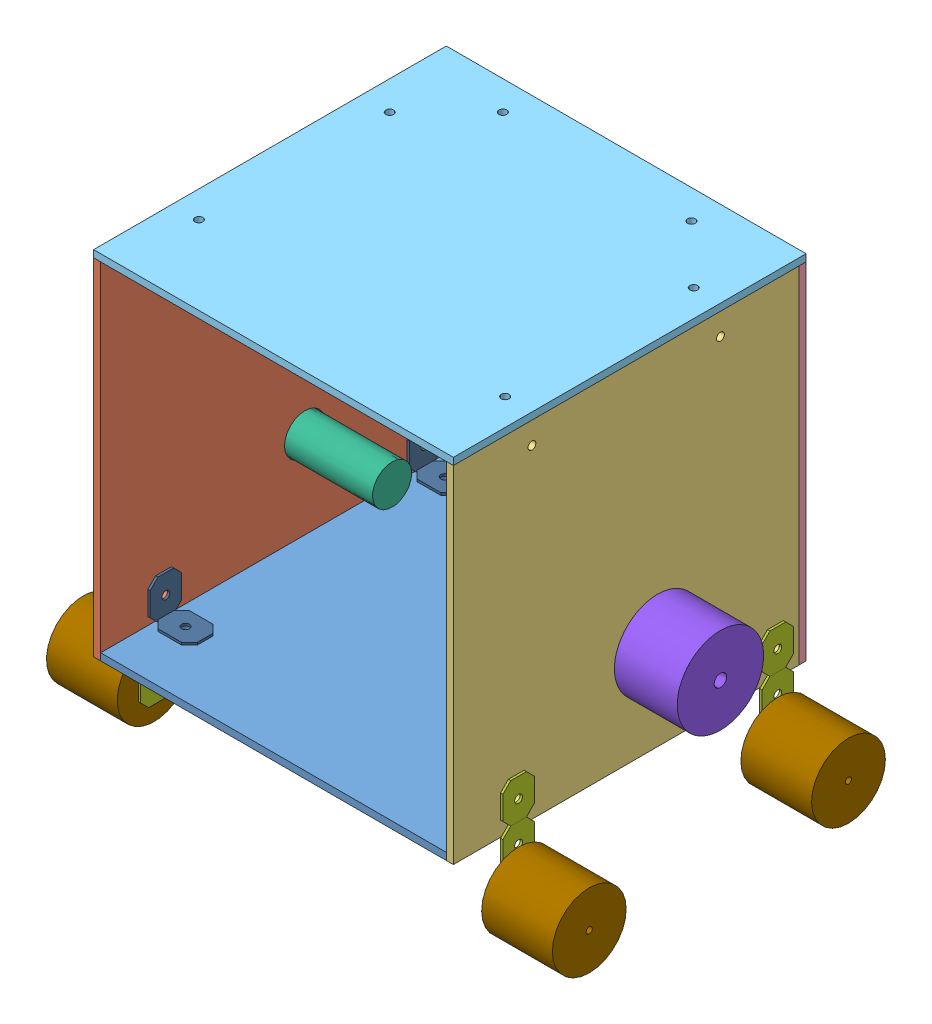
SolidWorks assembly walle, configuration Default. Lengths in mm.
Overall size (322 289.64 228.5).
29 component instances, 10 part files, 77 mates.
Components (placement in the parent):
- bottom-1: bottom [Default] at (91.1986 106.7408 168.0304) size (220 4.5 220)
- left-1: left [Default] at (-18.8014 216.7408 168.0304) x (0 0 1) z (0 -1 0) size (220 4.5 220)
- right-1: right [Default] at (201.1986 216.7408 168.0304) x (0 0 -1) z (0 -1 0) size (220 4.5 220)
- back-1: back [Default] at (91.1986 216.7408 58.0304) x (1 0 0) z (0 1 0) size (229 4.5 220)
- top-1: top [Default] at (91.1986 326.7408 165.7804) size (229 4.5 224.5)
- motor-1: motor [Default] at (36.6986 166.7408 148.0304) x (0 -0.263178 0.964747) z (0 -0.964747 -0.263178) size (25 70 25)
- motor-2: motor [Default] at (145.6986 163.3094 148.0304) x (0 0.57906 -0.815285) z (0 -0.815285 -0.57906) size (25 70 25)
- legs-1: legs [Default] at (-11.4617 88.7118 53.8984) x (0 1 0) z (0 0 1) size (75 1.5 20)
- legs-2: legs [Default] at (-36.6412 108.7699 218.8984) x (0 -1 0) z (0 0 1) size (75 1.5 20)
- legs-3: legs [Default] at (193.8588 108.7699 218.8984) x (0 -1 0) z (0 0 1) size (75 1.5 20)
- legs-4: legs [Default] at (193.8588 108.7699 53.8984) x (0 -1 0) z (0 0 1) size (75 1.5 20)
- big wheel-1: big wheel [Default] at (-23.3014 166.7408 148.0304) x (0 0.828484 0.560012) z (0 -0.560012 0.828484) size (55 40 55)
- big wheel-2: big wheel [Default] at (245.6986 163.3094 148.0304) x (0 -0.121677 0.99257) z (0 -0.99257 -0.121677) size (55 40 55)
- side wheels-1: side wheels [Default] at (-69.8014 73.7408 73.0304) x (0 -1 0) z (0 0 1) size (47 45 47)
- side wheels-2: side wheels [Default] at (-24.8014 73.7408 238.0304) x (0 0.863971 -0.503542) z (0 0.503542 0.863971) size (47 45 47)
- side wheels-3: side wheels [Default] at (252.1986 73.7408 238.0304) x (0 1 0) z (0 0 1) size (47 45 47)
- side wheels-4: side wheels [Default] at (252.1986 73.7408 73.0304) x (0 1 0) z (0 0 1) size (47 45 47)
- 2arm-1: 2arm [Default] at (10.1695 99.4011 218.8984) size (26.5 25 20)
- 2arm-2: 2arm [Default] at (10.1695 99.4011 53.8984) size (26.5 25 20)
- 2arm-3: 2arm [Default] at (50.3305 99.4011 87.0013) x (0 0 1) z (-1 0 0) size (26.5 25 20)
- 2arm-4: 2arm [Default] at (170.3305 99.4011 87.0013) x (0 0 1) z (-1 0 0) size (26.5 25 20)
- 2arm-5: 2arm [Default] at (172.2276 99.4011 92.1623) x (-1 0 0) z (0 0 -1) size (26.5 25 20)
- 2arm-6: 2arm [Default] at (172.2276 99.4011 257.1623) x (-1 0 0) z (0 0 -1) size (26.5 25 20)
- 2arm-7: 2arm [Default] at (12.0666 338.5806 87.0013) x (0 0 1) z (1 0 0) size (26.5 25 20)
- 2arm-8: 2arm [Default] at (132.0666 338.5806 87.0013) x (0 0 1) z (1 0 0) size (26.5 25 20)
- 2arm-9: 2arm [Default] at (-30.6412 297.7699 208.8984) x (0 -1 0) z (0 0 1) size (26.5 25 20)
- 2arm-10: 2arm [Default] at (213.0383 297.7699 247.1623) x (0 -1 0) z (0 0 -1) size (26.5 25 20)
- 2arm-11: 2arm [Default] at (213.0383 297.7699 127.1623) x (0 -1 0) z (0 0 -1) size (26.5 25 20)
- 2arm-12: 2arm [Default] at (10.1695 338.5806 127.1623) x (1 0 0) z (0 0 -1) size (26.5 25 20)
Mates (geometry in assembly coordinates):
- Coincident1: coincident anti-aligned: plane of bottom-1 through (201.1986 111.2408 278.0304) normal (1 0 0); plane of right-1 through (201.1986 216.7408 168.0304) normal (-1 0 0)
- Coincident2: coincident aligned: plane of bottom-1 through (91.1986 106.7408 168.0304) normal (0 -1 0); plane of right-1 through (205.6986 106.7408 278.0304) normal (0 -1 0)
- Coincident3: coincident aligned: plane of bottom-1 through (-18.8014 111.2408 278.0304) normal (0 0 1); plane of right-1 through (205.6986 106.7408 278.0304) normal (0 0 1)
- Coincident4: coincident aligned: plane of bottom-1 through (91.1986 106.7408 168.0304) normal (0 -1 0); plane of left-1 through (-23.3014 106.7408 58.0304) normal (0 -1 0)
- Coincident5: coincident anti-aligned: plane of bottom-1 through (-18.8014 111.2408 278.0304) normal (-1 0 0); plane of left-1 through (-18.8014 216.7408 168.0304) normal (1 0 0)
- Coincident6: coincident aligned: plane of bottom-1 through (-18.8014 111.2408 278.0304) normal (0 0 1); plane of left-1 through (-23.3014 106.7408 278.0304) normal (0 0 1)
- Coincident10: coincident aligned: plane of right-1 through (205.6986 216.7408 168.0304) normal (1 0 0); plane of back-1 through (205.6986 326.7408 53.5304) normal (1 0 0)
- Coincident11: coincident aligned: plane of bottom-1 through (91.1986 106.7408 168.0304) normal (0 -1 0); plane of back-1 through (-23.3014 106.7408 53.5304) normal (0 -1 0)
- Coincident12: coincident anti-aligned: plane of right-1 through (205.6986 106.7408 58.0304) normal (0 0 -1); plane of back-1 through (91.1986 216.7408 58.0304) normal (0 0 1)
- Coincident13: coincident aligned: plane of left-1 through (-23.3014 106.7408 278.0304) normal (0 0 1); plane of top-1 through (-23.3014 331.2408 278.0304) normal (0 0 1)
- Coincident14: coincident anti-aligned: plane of left-1 through (-23.3014 326.7408 58.0304) normal (0 1 0); plane of top-1 through (91.1986 326.7408 165.7804) normal (0 -1 0)
- Coincident15: coincident aligned: plane of left-1 through (-23.3014 216.7408 168.0304) normal (-1 0 0); plane of top-1 through (-23.3014 331.2408 278.0304) normal (-1 0 0)
- Concentric1: concentric anti-aligned: cylinder of right-1 through (201.1976 163.3094 148.0304) axis (1 0 0) radius 13; cylinder of motor-2 through (215.6986 163.3094 148.0304) axis (-1 0 0) radius 2
- Concentric2: concentric anti-aligned: cylinder of left-1 through (-18.8004 166.7408 148.0304) axis (-1 0 0) radius 13; cylinder of motor-1 through (-33.3014 166.7408 148.0304) axis (1 0 0) radius 2
- Coincident26: coincident anti-aligned: plane of left-1 through (-23.3014 216.7408 168.0304) normal (-1 0 0); plane of legs-2 through (-23.3014 123.7408 238.0304) normal (1 0 0)
- Coincident28: coincident anti-aligned: plane of left-1 through (-23.3014 216.7408 168.0304) normal (-1 0 0); plane of legs-1 through (-23.3014 123.7408 73.0304) normal (1 0 0)
- Coincident30: coincident anti-aligned: plane of right-1 through (205.6986 216.7408 168.0304) normal (1 0 0); plane of legs-3 through (205.6986 123.7408 238.0304) normal (-1 0 0)
- Coincident31: coincident anti-aligned: plane of right-1 through (205.6986 216.7408 168.0304) normal (1 0 0); plane of legs-4 through (205.6986 123.7408 73.0304) normal (-1 0 0)
- Coincident32: coincident aligned: plane of left-1 through (-23.3014 216.7408 168.0304) normal (-1 0 0); plane of motor-1 through (-23.3014 166.7408 148.0304) normal (-1 0 0)
- Coincident33: coincident aligned: plane of right-1 through (205.6986 216.7408 168.0304) normal (1 0 0); plane of motor-2 through (205.6986 163.3094 148.0304) normal (1 0 0)
- Concentric3: concentric anti-aligned: cylinder of motor-1 through (-33.3014 166.7408 148.0304) axis (1 0 0) radius 2; cylinder of big wheel-1 through (-23.3014 166.7408 148.0304) axis (-1 0 0) radius 4
- Coincident34: coincident anti-aligned: plane of left-1 through (-23.3014 216.7408 168.0304) normal (-1 0 0); plane of big wheel-1 through (-23.3014 166.7408 148.0304) normal (1 0 0)
- Concentric4: concentric aligned: cylinder of motor-2 through (215.6986 163.3094 148.0304) axis (-1 0 0) radius 2; cylinder of big wheel-2 through (245.6986 163.3094 148.0304) axis (-1 0 0) radius 4
- Coincident35: coincident anti-aligned: plane of right-1 through (205.6986 216.7408 168.0304) normal (1 0 0); plane of big wheel-2 through (205.6986 163.3094 148.0304) normal (-1 0 0)
- Concentric5: concentric anti-aligned: cylinder of legs-2 through (-24.8014 73.7408 238.0304) axis (1 0 0) radius 2.5; cylinder of side wheels-2 through (-24.8004 73.7408 238.0304) axis (-1 0 0) radius 2
- Coincident36: coincident anti-aligned: plane of legs-2 through (-24.8014 73.7408 238.0304) normal (-1 0 0); plane of side wheels-2 through (-24.8014 73.7408 238.0304) normal (1 0 0)
- Coincident37: coincident anti-aligned: plane of legs-1 through (-24.8014 73.7408 73.0304) normal (-1 0 0); plane of side wheels-1 through (-24.8014 73.7408 73.0304) normal (1 0 0)
- Concentric6: concentric anti-aligned: cylinder of legs-1 through (-23.3014 73.7408 73.0304) axis (-1 0 0) radius 2.5; cylinder of side wheels-1 through (-69.8024 73.7408 73.0304) axis (1 0 0) radius 2
- Coincident38: coincident anti-aligned: plane of legs-4 through (207.1986 73.7408 73.0304) normal (1 0 0); plane of side wheels-4 through (207.1986 73.7408 73.0304) normal (-1 0 0)
- Concentric7: concentric anti-aligned: cylinder of legs-4 through (205.6986 73.7408 73.0304) axis (1 0 0) radius 2.5; cylinder of side wheels-4 through (252.1996 73.7408 73.0304) axis (-1 0 0) radius 2
- Coincident39: coincident anti-aligned: plane of legs-3 through (207.1986 73.7408 238.0304) normal (1 0 0); plane of side wheels-3 through (207.1986 73.7408 238.0304) normal (-1 0 0)
- Concentric8: concentric anti-aligned: cylinder of legs-3 through (205.6986 73.7408 238.0304) axis (1 0 0) radius 2.5; cylinder of side wheels-3 through (252.1996 73.7408 238.0304) axis (-1 0 0) radius 2
- Concentric9: concentric aligned: circle of left-1; circle of legs-1
- Parallel1: parallel anti-aligned: plane of left-1 through (-23.3014 106.7408 58.0304) normal (0 -1 0); plane of legs-1 through (-24.8014 136.2408 63.0304) normal (0 1 0)
- Concentric10: concentric anti-aligned: cylinder of left-1 through (-18.8004 123.7408 238.0304) axis (-1 0 0) radius 2.75; cylinder of legs-2 through (-24.8014 123.7408 238.0304) axis (1 0 0) radius 2.5
- Parallel2: parallel anti-aligned: plane of left-1 through (-23.3014 106.7408 58.0304) normal (0 -1 0); plane of legs-2 through (-23.3014 136.2408 228.0304) normal (0 1 0)
- Concentric11: concentric aligned: cylinder of right-1 through (201.1976 123.7408 238.0304) axis (1 0 0) radius 2.5; cylinder of legs-3 through (205.6986 123.7408 238.0304) axis (1 0 0) radius 2.5
- Parallel3: parallel anti-aligned: plane of right-1 through (205.6986 106.7408 278.0304) normal (0 -1 0); plane of legs-3 through (207.1986 136.2408 228.0304) normal (0 1 0)
- Concentric12: concentric aligned: cylinder of right-1 through (201.1976 123.7408 73.0304) axis (1 0 0) radius 2.5; cylinder of legs-4 through (205.6986 123.7408 73.0304) axis (1 0 0) radius 2.5
- Parallel4: parallel anti-aligned: plane of right-1 through (205.6986 106.7408 278.0304) normal (0 -1 0); plane of legs-4 through (207.1986 136.2408 63.0304) normal (0 1 0)
- Coincident40: coincident anti-aligned: plane of left-1 through (-18.8014 216.7408 168.0304) normal (1 0 0); plane of 2arm-1 through (-18.8014 123.7408 238.0304) normal (-1 0 0)
- Coincident41: coincident anti-aligned: plane of bottom-1 through (91.1986 111.2408 168.0304) normal (0 1 0); plane of 2arm-1 through (-4.8014 111.2408 238.0304) normal (0 -1 0)
- Coincident42: coincident anti-aligned: plane of left-1 through (-18.8014 216.7408 168.0304) normal (1 0 0); plane of 2arm-2 through (-18.8014 123.7408 73.0304) normal (-1 0 0)
- Coincident43: coincident anti-aligned: plane of bottom-1 through (91.1986 111.2408 168.0304) normal (0 1 0); plane of 2arm-2 through (-4.8014 111.2408 73.0304) normal (0 -1 0)
- Coincident44: coincident anti-aligned: plane of right-1 through (201.1986 216.7408 168.0304) normal (-1 0 0); plane of 2arm-5 through (201.1986 123.7408 73.0304) normal (1 0 0)
- Coincident45: coincident anti-aligned: plane of bottom-1 through (91.1986 111.2408 168.0304) normal (0 1 0); plane of 2arm-5 through (187.1986 111.2408 73.0304) normal (0 -1 0)
- Coincident46: coincident anti-aligned: plane of right-1 through (201.1986 216.7408 168.0304) normal (-1 0 0); plane of 2arm-6 through (201.1986 123.7408 238.0304) normal (1 0 0)
- Coincident47: coincident anti-aligned: plane of bottom-1 through (91.1986 111.2408 168.0304) normal (0 1 0); plane of 2arm-6 through (187.1986 111.2408 238.0304) normal (0 -1 0)
- Coincident52: coincident anti-aligned: plane of back-1 through (91.1986 216.7408 58.0304) normal (0 0 1); plane of 2arm-7 through (31.1986 314.2408 58.0304) normal (0 0 -1)
- Coincident53: coincident anti-aligned: plane of top-1 through (91.1986 326.7408 165.7804) normal (0 -1 0); plane of 2arm-7 through (31.1986 326.7408 72.0304) normal (0 1 0)
- Coincident54: coincident anti-aligned: plane of top-1 through (91.1986 326.7408 165.7804) normal (0 -1 0); plane of 2arm-8 through (151.1986 326.7408 72.0304) normal (0 1 0)
- Coincident55: coincident anti-aligned: plane of back-1 through (91.1986 216.7408 58.0304) normal (0 0 1); plane of 2arm-8 through (151.1986 314.2408 58.0304) normal (0 0 -1)
- Coincident56: coincident anti-aligned: plane of left-1 through (-18.8014 216.7408 168.0304) normal (1 0 0); plane of 2arm-9 through (-18.8014 312.7408 228.0304) normal (-1 0 0)
- Coincident57: coincident anti-aligned: plane of top-1 through (91.1986 326.7408 165.7804) normal (0 -1 0); plane of 2arm-9 through (-6.3014 326.7408 228.0304) normal (0 1 0)
- Concentric13: concentric anti-aligned: cylinder of left-1 through (-18.8004 123.7408 238.0304) axis (-1 0 0) radius 2.75; cylinder of 2arm-1 through (-18.8014 123.7408 238.0304) axis (1 0 0) radius 2.5
- Concentric14: concentric anti-aligned: cylinder of left-1 through (-18.8004 123.7408 73.0304) axis (-1 0 0) radius 2.75; cylinder of 2arm-2 through (-18.8014 123.7408 73.0304) axis (1 0 0) radius 2.5
- Concentric15: concentric anti-aligned: cylinder of right-1 through (201.1976 123.7408 238.0304) axis (1 0 0) radius 2.5; cylinder of 2arm-6 through (201.1986 123.7408 238.0304) axis (-1 0 0) radius 2.5
- Concentric16: concentric anti-aligned: cylinder of right-1 through (201.1976 123.7408 73.0304) axis (1 0 0) radius 2.5; cylinder of 2arm-5 through (201.1986 123.7408 73.0304) axis (-1 0 0) radius 2.5
- Coincident61: coincident anti-aligned: plane of bottom-1 through (91.1986 111.2408 168.0304) normal (0 1 0); plane of 2arm-3 through (31.1986 111.2408 72.0304) normal (0 -1 0)
- Coincident62: coincident anti-aligned: plane of back-1 through (91.1986 216.7408 58.0304) normal (0 0 1); plane of 2arm-3 through (31.1986 123.7408 58.0304) normal (0 0 -1)
- Distance1: distance = 40 mm anti-aligned: plane of 2arm-3 through (21.1986 136.2408 59.5304) normal (-1 0 0); plane of left-1 through (-18.8014 216.7408 168.0304) normal (1 0 0)
- Coincident63: coincident anti-aligned: plane of back-1 through (91.1986 216.7408 58.0304) normal (0 0 1); plane of 2arm-4 through (151.1986 123.7408 58.0304) normal (0 0 -1)
- Coincident65: coincident anti-aligned: plane of back-1 through (91.1986 216.7408 58.0304) normal (0 0 1); plane of 2arm-4 through (151.1986 123.7408 58.0304) normal (0 0 -1)
- Coincident66: coincident anti-aligned: plane of bottom-1 through (91.1986 111.2408 168.0304) normal (0 1 0); plane of 2arm-4 through (151.1986 111.2408 72.0304) normal (0 -1 0)
- Distance2: distance = 40 mm anti-aligned: plane of 2arm-4 through (161.1986 136.2408 59.5304) normal (1 0 0); plane of right-1 through (201.1986 216.7408 168.0304) normal (-1 0 0)
- Coincident68: coincident anti-aligned: plane of left-1 through (-18.8014 216.7408 168.0304) normal (1 0 0); plane of 2arm-12 through (-18.8014 314.2408 108.0304) normal (-1 0 0)
- Coincident70: coincident anti-aligned: plane of top-1 through (91.1986 326.7408 165.7804) normal (0 -1 0); plane of 2arm-12 through (-4.8014 326.7408 108.0304) normal (0 1 0)
- Distance3: distance = 40 mm anti-aligned: plane of 2arm-12 through (-17.3014 325.2408 98.0304) normal (0 0 -1); plane of back-1 through (91.1986 216.7408 58.0304) normal (0 0 1)
- Distance5: distance = 40 mm aligned: plane of left-1 through (-23.3014 106.7408 278.0304) normal (0 0 1); plane of 2arm-9 through (-17.3014 325.2408 238.0304) normal (0 0 1)
- Coincident72: coincident anti-aligned: plane of top-1 through (91.1986 326.7408 165.7804) normal (0 -1 0); plane of 2arm-11 through (188.6986 326.7408 108.0304) normal (0 1 0)
- Coincident74: coincident anti-aligned: plane of right-1 through (201.1986 216.7408 168.0304) normal (-1 0 0); plane of 2arm-11 through (201.1986 312.7408 108.0304) normal (1 0 0)
- Distance6: distance = 40 mm anti-aligned: plane of 2arm-11 through (199.6986 325.2408 98.0304) normal (0 0 -1); plane of back-1 through (91.1986 216.7408 58.0304) normal (0 0 1)
- Coincident77: coincident anti-aligned: plane of top-1 through (91.1986 326.7408 165.7804) normal (0 -1 0); plane of 2arm-10 through (188.6986 326.7408 228.0304) normal (0 1 0)
- Coincident78: coincident anti-aligned: plane of right-1 through (201.1986 216.7408 168.0304) normal (-1 0 0); plane of 2arm-10 through (201.1986 312.7408 228.0304) normal (1 0 0)
- Distance7: distance = 40 mm aligned: plane of 2arm-10 through (199.6986 325.2408 238.0304) normal (0 0 1); plane of right-1 through (205.6986 106.7408 278.0304) normal (0 0 1)
- Distance8: distance = 40 mm anti-aligned: plane of 2arm-7 through (21.1986 301.7408 59.5304) normal (-1 0 0); plane of left-1 through (-18.8014 216.7408 168.0304) normal (1 0 0)
- Distance9: distance = 40 mm anti-aligned: plane of 2arm-8 through (161.1986 301.7408 59.5304) normal (1 0 0); plane of right-1 through (201.1986 216.7408 168.0304) normal (-1 0 0)
